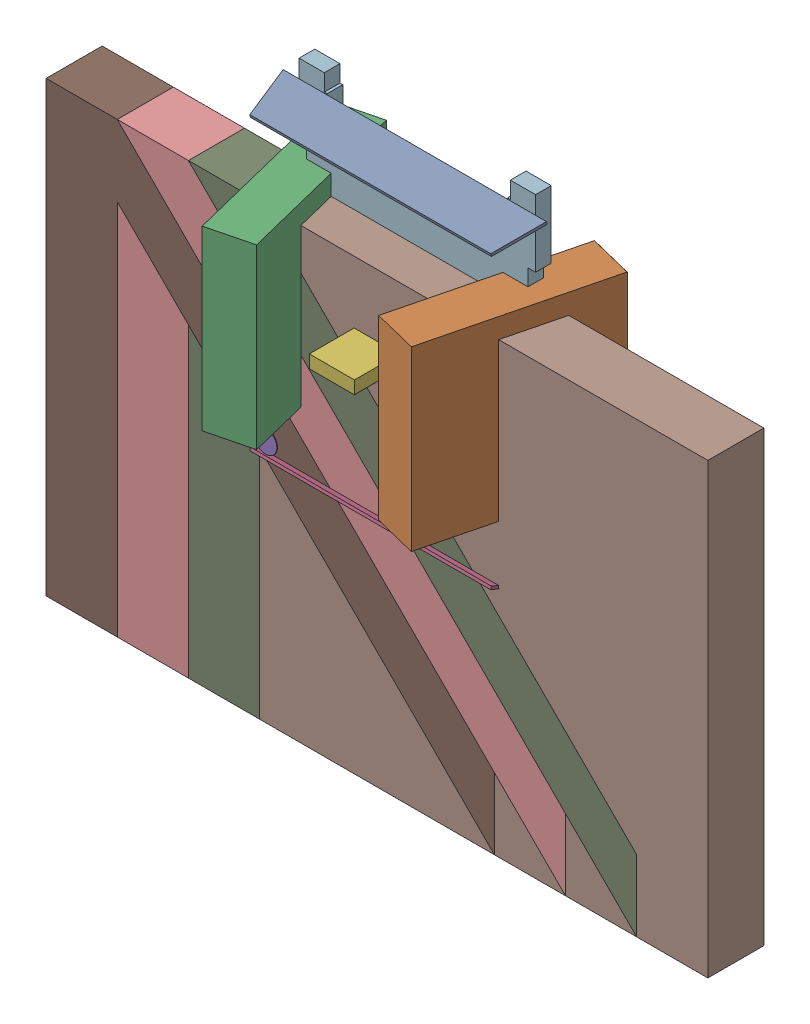
SolidWorks assembly PPAK-8, configuration 默认. Lengths in mm.
Overall size (11.81 9.85 3.29).
26 component instances, 7 part files, 0 mates.
Components (placement in the parent):
- User Library-DFN5x6_SO8FL-1: User Library-DFN5x6_SO8FL [默认] at (-1.905 -2.74 0) size (11.81 9.85 3.29)
  - Free-Models-1: Free-Models [默认] at origin size (11.81 9.85 3.29)
    - SIDE_S-1: SIDE_S [默认] at (1.9 5.4223 0.705) x (1 0 0) z (0 0.970296 0.241922) size (4.7 0.82 0.05)
      - Extruded-1: Extruded [默认] at origin size (4.7 0.82 0.05)
    - SIDE_L-1: SIDE_L [默认] at (4.1508 2.775 0.705) x (0.241922 0 -0.970296) z (-0.970296 0 -0.241922) size (3.19 3.17 0.81)
      - Extruded_2-1: Extruded_2 [默认] at origin size (3.19 3.17 0.81)
    - SIDE_L-1-1: SIDE_L-1 [默认] at (-0.3508 2.775 0.705) x (-0.241922 0 -0.970296) z (0.970296 0 -0.241922) size (3.19 3.17 0.81)
      - Extruded_2-1: Extruded_2 [默认] at origin size (3.19 3.17 0.81)
    - SIDE_S-1-1: SIDE_S-1 [默认] at (1.9 0.1277 0.705) x (-1 0 0) z (0 -0.970296 0.241922) size (4.7 0.82 0.05)
      - Extruded-1: Extruded [默认] at origin size (4.7 0.82 0.05)
    - 587257496-1: 587257496 [默认] at (0.0484 0.4796 1.12) size (0.4 0.4 0.01)
      - Cylinder-1: Cylinder [默认] at origin size (0.4 0.4 0.01)
    - 750905040-1: 750905040 [默认] at (1.9 2.775 1) size (0.8 0.23 0.8)
      - Extruded_3-1: Extruded_3 [默认] at origin size (0.8 0.23 0.8)
    - 266863104-1: 266863104 [默认] at (1.9025 2.775 0.02) size (0.8 1.14 0.8)
      - Extruded_4-1: Extruded_4 [默认] at origin size (0.8 1.14 0.8)
    - 500156144-1: 500156144 [默认] at (3.81 0 0) size (8 8 1)
      - Extruded_5-1: Extruded_5 [默认] at origin size (8 8 1)
    - 500156144-1-1: 500156144-1 [默认] at (2.54 0 0) size (8 8 1)
      - Extruded_5-1: Extruded_5 [默认] at origin size (8 8 1)
    - 500156144-2-1: 500156144-2 [默认] at (1.27 0 0) size (8 8 1)
      - Extruded_5-1: Extruded_5 [默认] at origin size (8 8 1)
    - 500156144-3-1: 500156144-3 [默认] at origin size (8 8 1)
      - Extruded_5-1: Extruded_5 [默认] at origin size (8 8 1)
    - 500160368-1: 500160368 [默认] at (1.905 3.335 0) size (5.15 5.03 0.28)
      - Extruded_6-1: Extruded_6 [默认] at origin size (5.15 5.03 0.28)
